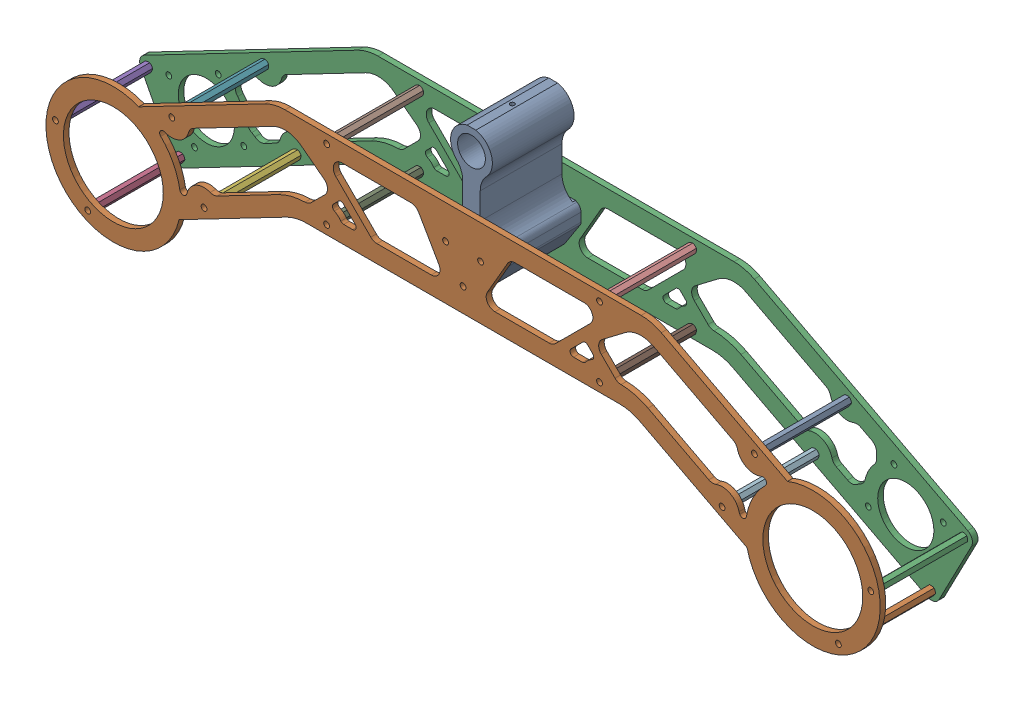
SolidWorks assembly Bogie Assy-2023, configuration Default. Lengths in mm.
Overall size (477.1 154.34 56.35).
15 component instances, 4 part files, 54 mates.
Components (placement in the parent):
- Bogie Adapter-2023-1: Bogie Adapter-2023 [Default] at origin size (28.5 80.48 50)
- Bogie Plate - Inner-2023-1: Bogie Plate - Inner-2023 [Default] at (0 0 25) size (477.1 114.66 3.17)
- Bogie Plate - Outer-2023-1: Bogie Plate - Outer-2023 [Default] at (0 0 -28.175) size (476.26 111.29 3.17)
- Standoff Nut-2023-1: Standoff Nut-2023 [95947A502] at (-214.6584 -134.2918 -25) x (0 0 1) z (-1 0 0) size (50 4.5 5.2)
- Standoff Nut-2023-13: Standoff Nut-2023 [95947A502] at (-233.1284 -98.8113 -25) x (0 0 1) z (-0.987351 -0.158553 0) size (50 4.5 5.2)
- Standoff Nut-2023-14: Standoff Nut-2023 [95947A502] at (-148.1326 -99.6606 -25) x (0 0 1) z (-0.959125 -0.282984 0) size (50 4.5 5.2)
- Standoff Nut-2023-15: Standoff Nut-2023 [95947A502] at (-166.6026 -64.1802 -25) x (0 0 1) z (-0.928571 -0.371154 0) size (50 4.5 5.2)
- Standoff Nut-2023-16: Standoff Nut-2023 [95947A502] at (-78.0312 -33 -25) x (0 0 1) z (-0.906989 -0.421154 0) size (50 4.5 5.2)
- Standoff Nut-2023-17: Standoff Nut-2023 [95947A502] at (-78.0312 -73 -25) x (0 0 1) z (-0.992592 -0.121498 0) size (50 4.5 5.2)
- Standoff Nut-2023-18: Standoff Nut-2023 [95947A502] at (78.0312 -33 -25) x (0 0 1) z (-0.919615 -0.39282 0) size (50 4.5 5.2)
- Standoff Nut-2023-19: Standoff Nut-2023 [95947A502] at (78.0312 -73 -25) x (0 0 1) z (-0.952324 -0.305088 0) size (50 4.5 5.2)
- Standoff Nut-2023-20: Standoff Nut-2023 [95947A502] at (148.1326 -99.6606 -25) x (0 0 1) z (-0.985697 -0.168526 0) size (50 4.5 5.2)
- Standoff Nut-2023-21: Standoff Nut-2023 [95947A502] at (166.6026 -64.1802 -25) x (0 0 1) z (-1 0 0) size (50 4.5 5.2)
- Standoff Nut-2023-22: Standoff Nut-2023 [95947A502] at (214.6584 -134.2918 -25) x (0 0 1) z (-0.985697 0.168526 0) size (50 4.5 5.2)
- Standoff Nut-2023-23: Standoff Nut-2023 [95947A502] at (233.1284 -98.8113 -25) x (0 0 1) z (-0.952324 0.305088 0) size (50 4.5 5.2)
Mates (geometry in assembly coordinates):
- Concentric1: concentric anti-aligned: cylinder of Bogie Adapter-1 through (10 -47.2265 15) axis (0 0 1) radius 1.25; cylinder of Bogie Plate - Inner-1 through (10 -47.2265 28.175) axis (0 0 -1) radius 1.65
- Concentric2: concentric anti-aligned: cylinder of Bogie Adapter-1 through (-10 -47.2265 15) axis (0 0 1) radius 1.25; cylinder of Bogie Plate - Inner-1 through (-10 -47.2265 28.175) axis (0 0 -1) radius 1.65
- Coincident1: coincident anti-aligned: plane of Bogie Adapter-1 through (0 0 25) normal (0 0 1); plane of Bogie Plate - Inner-1 through (-233.1284 -98.8113 25) normal (0 0 -1)
- Concentric3: concentric aligned: cylinder of Bogie Adapter-1 through (10 -47.2265 -15) axis (0 0 -1) radius 1.25; cylinder of Bogie Plate - Outer-1 through (10 -47.2265 -25) axis (0 0 -1) radius 1.65
- Concentric5: concentric aligned: cylinder of Bogie Adapter-1 through (-10 -47.2265 -15) axis (0 0 -1) radius 1.25; cylinder of Bogie Plate - Outer-1 through (-10 -47.2265 -25) axis (0 0 -1) radius 1.65
- Coincident2: coincident anti-aligned: plane of Bogie Adapter-1 through (0 0 -25) normal (0 0 -1); plane of Bogie Plate - Outer-1 through (-233.1284 -98.8113 -25) normal (0 0 1)
- Concentric6: concentric anti-aligned: cylinder of Bogie Plate - Inner-1 through (-214.6584 -134.2918 25) axis (0 0 1) radius 1.65; cylinder of Standoff Nut-1 through (-214.6584 -134.2918 -25) axis (0 0 -1) radius 1.5
- Coincident3: coincident anti-aligned: plane of Bogie Plate - Inner-1 through (-233.1284 -98.8113 25) normal (0 0 -1); plane of Standoff Nut-1 through (-214.6584 -134.2918 25) normal (0 0 1)
- Concentric7: concentric anti-aligned: cylinder of Bogie Plate - Outer-1 through (-214.6584 -134.2918 -28.175) axis (0 0 1) radius 1.65; cylinder of Standoff Nut-1 through (-214.6584 -134.2918 -25) axis (0 0 -1) radius 1.5
- Coincident4: coincident anti-aligned: plane of Bogie Plate - Outer-1 through (-233.1284 -98.8113 -25) normal (0 0 1); plane of Standoff Nut-1 through (-214.6584 -134.2918 -25) normal (0 0 -1)
- Coincident5: coincident anti-aligned: plane of Bogie Plate - Inner-1 through (-233.1284 -98.8113 25) normal (0 0 -1); plane of Standoff Nut-13 through (-233.1284 -98.8113 25) normal (0 0 1)
- Coincident6: coincident anti-aligned: plane of Bogie Plate - Outer-1 through (-233.1284 -98.8113 -25) normal (0 0 1); plane of Standoff Nut-13 through (-233.1284 -98.8113 -25) normal (0 0 -1)
- Concentric8: concentric anti-aligned: cylinder of Bogie Plate - Inner-1 through (-233.1284 -98.8113 25) axis (0 0 1) radius 1.65; cylinder of Standoff Nut-13 through (-233.1284 -98.8113 -25) axis (0 0 -1) radius 1.5
- Concentric9: concentric anti-aligned: cylinder of Bogie Plate - Outer-1 through (-233.1284 -98.8113 -28.175) axis (0 0 1) radius 1.65; cylinder of Standoff Nut-13 through (-233.1284 -98.8113 -25) axis (0 0 -1) radius 1.5
- Coincident7: coincident anti-aligned: plane of Bogie Plate - Inner-1 through (-233.1284 -98.8113 25) normal (0 0 -1); plane of Standoff Nut-14 through (-148.1326 -99.6606 25) normal (0 0 1)
- Coincident8: coincident anti-aligned: plane of Bogie Plate - Outer-1 through (-233.1284 -98.8113 -25) normal (0 0 1); plane of Standoff Nut-14 through (-148.1326 -99.6606 -25) normal (0 0 -1)
- Concentric10: concentric anti-aligned: cylinder of Bogie Plate - Inner-1 through (-148.1326 -99.6606 25) axis (0 0 1) radius 1.65; cylinder of Standoff Nut-14 through (-148.1326 -99.6606 -25) axis (0 0 -1) radius 1.5
- Concentric11: concentric anti-aligned: cylinder of Bogie Plate - Outer-1 through (-148.1326 -99.6606 -28.175) axis (0 0 1) radius 1.65; cylinder of Standoff Nut-14 through (-148.1326 -99.6606 -25) axis (0 0 -1) radius 1.5
- Coincident9: coincident anti-aligned: plane of Bogie Plate - Inner-1 through (-233.1284 -98.8113 25) normal (0 0 -1); plane of Standoff Nut-15 through (-166.6026 -64.1802 25) normal (0 0 1)
- Coincident10: coincident anti-aligned: plane of Bogie Plate - Outer-1 through (-233.1284 -98.8113 -25) normal (0 0 1); plane of Standoff Nut-15 through (-166.6026 -64.1802 -25) normal (0 0 -1)
- Concentric12: concentric anti-aligned: cylinder of Bogie Plate - Inner-1 through (-166.6026 -64.1802 25) axis (0 0 1) radius 1.65; cylinder of Standoff Nut-15 through (-166.6026 -64.1802 -25) axis (0 0 -1) radius 1.5
- Concentric13: concentric anti-aligned: cylinder of Bogie Plate - Outer-1 through (-166.6026 -64.1802 -28.175) axis (0 0 1) radius 1.65; cylinder of Standoff Nut-15 through (-166.6026 -64.1802 -25) axis (0 0 -1) radius 1.5
- Coincident11: coincident anti-aligned: plane of Bogie Plate - Inner-1 through (-233.1284 -98.8113 25) normal (0 0 -1); plane of Standoff Nut-16 through (-78.0312 -33 25) normal (0 0 1)
- Coincident12: coincident anti-aligned: plane of Bogie Plate - Outer-1 through (-233.1284 -98.8113 -25) normal (0 0 1); plane of Standoff Nut-16 through (-78.0312 -33 -25) normal (0 0 -1)
- Concentric14: concentric anti-aligned: cylinder of Bogie Plate - Inner-1 through (-78.0312 -33 25) axis (0 0 1) radius 1.65; cylinder of Standoff Nut-16 through (-78.0312 -33 -25) axis (0 0 -1) radius 1.5
- Concentric15: concentric anti-aligned: cylinder of Bogie Plate - Outer-1 through (-78.0312 -33 -28.175) axis (0 0 1) radius 1.65; cylinder of Standoff Nut-16 through (-78.0312 -33 -25) axis (0 0 -1) radius 1.5
- Coincident13: coincident anti-aligned: plane of Bogie Plate - Inner-1 through (-233.1284 -98.8113 25) normal (0 0 -1); plane of Standoff Nut-17 through (-78.0312 -73 25) normal (0 0 1)
- Coincident14: coincident anti-aligned: plane of Bogie Plate - Outer-1 through (-233.1284 -98.8113 -25) normal (0 0 1); plane of Standoff Nut-17 through (-78.0312 -73 -25) normal (0 0 -1)
- Concentric16: concentric anti-aligned: cylinder of Bogie Plate - Inner-1 through (-78.0312 -73 25) axis (0 0 1) radius 1.65; cylinder of Standoff Nut-17 through (-78.0312 -73 -25) axis (0 0 -1) radius 1.5
- Concentric17: concentric anti-aligned: cylinder of Bogie Plate - Outer-1 through (-78.0312 -73 -28.175) axis (0 0 1) radius 1.65; cylinder of Standoff Nut-17 through (-78.0312 -73 -25) axis (0 0 -1) radius 1.5
- Coincident15: coincident anti-aligned: plane of Bogie Plate - Inner-1 through (-233.1284 -98.8113 25) normal (0 0 -1); plane of Standoff Nut-18 through (78.0312 -33 25) normal (0 0 1)
- Coincident16: coincident anti-aligned: plane of Bogie Plate - Outer-1 through (-233.1284 -98.8113 -25) normal (0 0 1); plane of Standoff Nut-18 through (78.0312 -33 -25) normal (0 0 -1)
- Concentric18: concentric anti-aligned: cylinder of Bogie Plate - Inner-1 through (78.0312 -33 25) axis (0 0 1) radius 1.65; cylinder of Standoff Nut-18 through (78.0312 -33 -25) axis (0 0 -1) radius 1.5
- Concentric19: concentric anti-aligned: cylinder of Bogie Plate - Outer-1 through (78.0312 -33 -28.175) axis (0 0 1) radius 1.65; cylinder of Standoff Nut-18 through (78.0312 -33 -25) axis (0 0 -1) radius 1.5
- Coincident17: coincident anti-aligned: plane of Bogie Plate - Inner-1 through (-233.1284 -98.8113 25) normal (0 0 -1); plane of Standoff Nut-19 through (78.0312 -73 25) normal (0 0 1)
- Coincident18: coincident anti-aligned: plane of Bogie Plate - Outer-1 through (-233.1284 -98.8113 -25) normal (0 0 1); plane of Standoff Nut-19 through (78.0312 -73 -25) normal (0 0 -1)
- Concentric20: concentric anti-aligned: cylinder of Bogie Plate - Inner-1 through (78.0312 -73 25) axis (0 0 1) radius 1.65; cylinder of Standoff Nut-19 through (78.0312 -73 -25) axis (0 0 -1) radius 1.5
- Concentric21: concentric anti-aligned: cylinder of Bogie Plate - Outer-1 through (78.0312 -73 -28.175) axis (0 0 1) radius 1.65; cylinder of Standoff Nut-19 through (78.0312 -73 -25) axis (0 0 -1) radius 1.5
- Coincident19: coincident anti-aligned: plane of Bogie Plate - Inner-1 through (-233.1284 -98.8113 25) normal (0 0 -1); plane of Standoff Nut-20 through (148.1326 -99.6606 25) normal (0 0 1)
- Coincident20: coincident anti-aligned: plane of Bogie Plate - Outer-1 through (-233.1284 -98.8113 -25) normal (0 0 1); plane of Standoff Nut-20 through (148.1326 -99.6606 -25) normal (0 0 -1)
- Concentric22: concentric anti-aligned: cylinder of Bogie Plate - Inner-1 through (148.1326 -99.6606 25) axis (0 0 1) radius 1.65; cylinder of Standoff Nut-20 through (148.1326 -99.6606 -25) axis (0 0 -1) radius 1.5
- Concentric23: concentric anti-aligned: cylinder of Bogie Plate - Outer-1 through (148.1326 -99.6606 -28.175) axis (0 0 1) radius 1.65; cylinder of Standoff Nut-20 through (148.1326 -99.6606 -25) axis (0 0 -1) radius 1.5
- Coincident21: coincident anti-aligned: plane of Bogie Plate - Inner-1 through (-233.1284 -98.8113 25) normal (0 0 -1); plane of Standoff Nut-21 through (166.6026 -64.1802 25) normal (0 0 1)
- Coincident22: coincident anti-aligned: plane of Bogie Plate - Outer-1 through (-233.1284 -98.8113 -25) normal (0 0 1); plane of Standoff Nut-21 through (166.6026 -64.1802 -25) normal (0 0 -1)
- Concentric24: concentric anti-aligned: cylinder of Bogie Plate - Inner-1 through (166.6026 -64.1802 25) axis (0 0 1) radius 1.65; cylinder of Standoff Nut-21 through (166.6026 -64.1802 -25) axis (0 0 -1) radius 1.5
- Concentric25: concentric anti-aligned: cylinder of Bogie Plate - Outer-1 through (166.6026 -64.1802 -28.175) axis (0 0 1) radius 1.65; cylinder of Standoff Nut-21 through (166.6026 -64.1802 -25) axis (0 0 -1) radius 1.5
- Coincident23: coincident anti-aligned: plane of Bogie Plate - Inner-1 through (-233.1284 -98.8113 25) normal (0 0 -1); plane of Standoff Nut-22 through (214.6584 -134.2918 25) normal (0 0 1)
- Coincident24: coincident anti-aligned: plane of Bogie Plate - Outer-1 through (-233.1284 -98.8113 -25) normal (0 0 1); plane of Standoff Nut-22 through (214.6584 -134.2918 -25) normal (0 0 -1)
- Concentric26: concentric anti-aligned: cylinder of Bogie Plate - Inner-1 through (214.6584 -134.2918 25) axis (0 0 1) radius 1.65; cylinder of Standoff Nut-22 through (214.6584 -134.2918 -25) axis (0 0 -1) radius 1.5
- Concentric27: concentric anti-aligned: cylinder of Bogie Plate - Outer-1 through (214.6584 -134.2918 -28.175) axis (0 0 1) radius 1.65; cylinder of Standoff Nut-22 through (214.6584 -134.2918 -25) axis (0 0 -1) radius 1.5
- Coincident25: coincident anti-aligned: plane of Bogie Plate - Inner-1 through (-233.1284 -98.8113 25) normal (0 0 -1); plane of Standoff Nut-23 through (233.1284 -98.8113 25) normal (0 0 1)
- Coincident26: coincident anti-aligned: plane of Bogie Plate - Outer-1 through (-233.1284 -98.8113 -25) normal (0 0 1); plane of Standoff Nut-23 through (233.1284 -98.8113 -25) normal (0 0 -1)
- Concentric28: concentric anti-aligned: cylinder of Bogie Plate - Inner-1 through (233.1284 -98.8113 25) axis (0 0 1) radius 1.65; cylinder of Standoff Nut-23 through (233.1284 -98.8113 -25) axis (0 0 -1) radius 1.5
- Concentric29: concentric anti-aligned: cylinder of Bogie Plate - Outer-1 through (233.1284 -98.8113 -28.175) axis (0 0 1) radius 1.65; cylinder of Standoff Nut-23 through (233.1284 -98.8113 -25) axis (0 0 -1) radius 1.5
